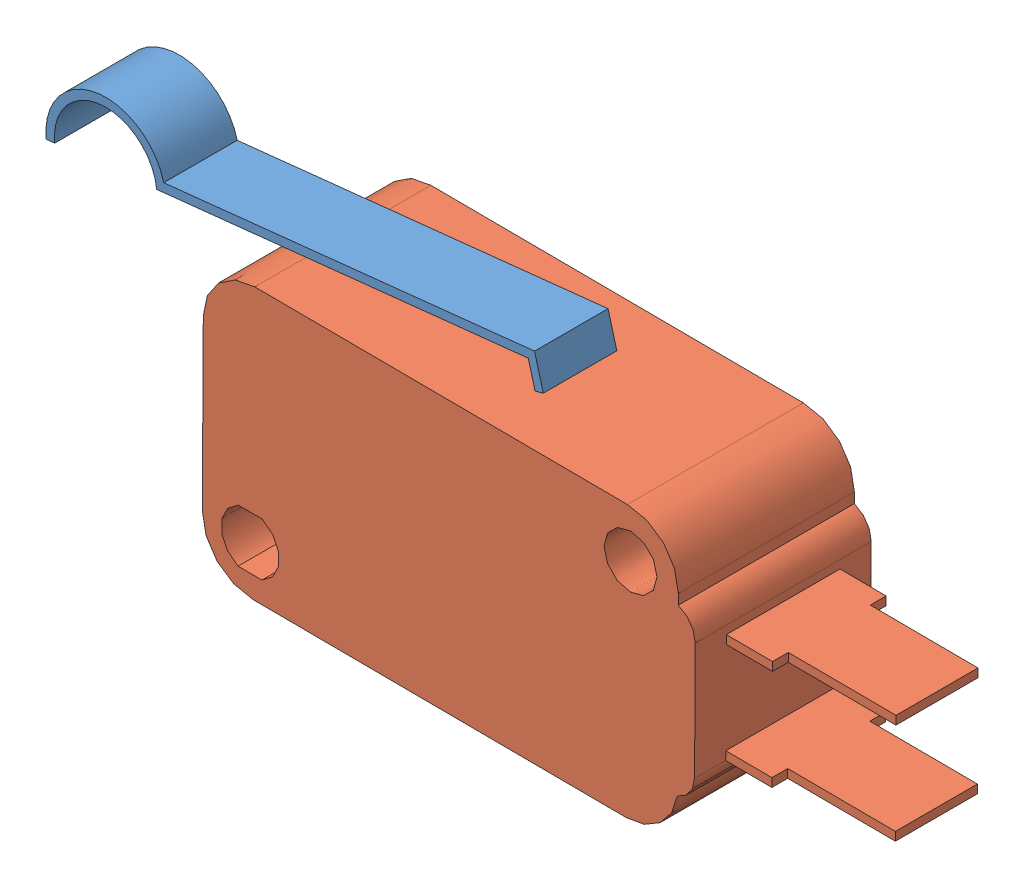
SolidWorks assembly D2RV_L13_FLAT, configuration Default. Lengths in mm.
Overall size (50.78 24.84 10.3).
2 component instances, 2 part files, 4 mates.
Components (placement in the parent):
- D2RV_L13_ACTUATOR-1: D2RV_L13_ACTUATOR [Default] at (-10.3561 11.1218 -1.9117) x (0.964534 0.26396 0) z (0 0 1) size (28.5 9 4.3)
- D2RV_L13_BASE_FLAT-1: D2RV_L13_BASE_FLAT [Default] at (-1.7725 8.2717 -1.9117) x (0.999983 -0.005825 0) z (0 0 1) size (37.8 15.9 10.3)
Mates (geometry in assembly coordinates):
- Distance2: distance = 16.4 mm: line of D2RV_L13_ACTUATOR-1 through (-10.3561 11.1218 0.2383) axis (0 0 -1); plane of D2RV_L13_BASE_FLAT-1 through (-26.7558 11.2173 3.2383) normal (-0.999983 0.005825 0)
- Coincident5: coincident: line of D2RV_L13_ACTUATOR-1 through (-10.3561 11.1218 0.2383) axis (0 0 -1); plane of D2RV_L13_BASE_FLAT-1 through (-26.7558 11.2173 3.2383) normal (0.005825 0.999983 0)
- Coincident6: coincident: plane of D2RV_L13_ACTUATOR-1 through (-10.3561 11.1218 -1.9117) normal (0 0 1); plane of D2RV_L13_BASE_FLAT-1 through (-1.7725 8.2717 -1.9117) normal (0 0 1)
- Coincident7: coincident: point of D2RV_L13_ACTUATOR-1; moEndPointRef_w of D2RV_L13_BASE_FLAT-1
